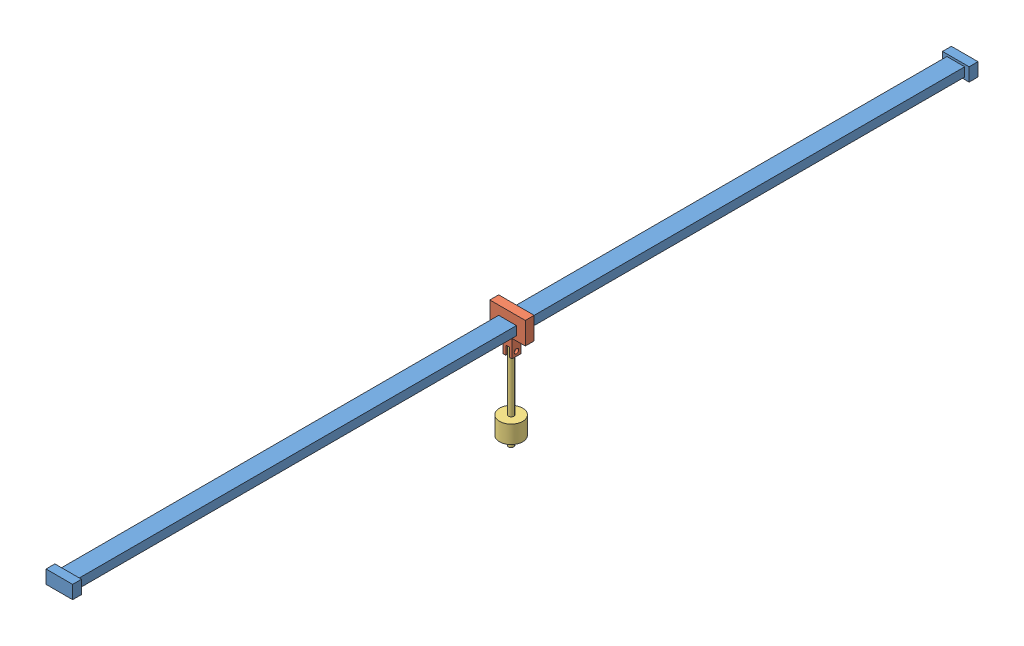
SolidWorks assembly PenduleTR, configuration Défaut. Lengths in mm.
Overall size (40 135 1020).
3 component instances, 3 part files, 7 mates.
Components (placement in the parent):
- bati-1: bati [Défaut] at (490.6862 31.3421 925.6549) size (30 15 1020)
- chariot-1: chariot [Défaut] at (490.6862 31.3421 925.6549) size (40 45 10)
- pendule-1: pendule [Défaut] at (489.6862 11.3421 925.6549) x (0 0 1) z (-1 0 0) size (26 100 26)
Mates (geometry in assembly coordinates):
- Coïncidente1: coincident anti-aligned: plane of bati-1 through (480.6862 26.3421 1425.6549) normal (0 -1 0); plane of chariot-1 through (480.6862 26.3421 920.6549) normal (0 1 0)
- Coïncidente2: coincident anti-aligned: plane of bati-1 through (480.6862 36.3421 1425.6549) normal (-1 0 0); plane of chariot-1 through (480.6862 36.3421 920.6549) normal (1 0 0)
- Coaxiale1: concentric anti-aligned: cylinder of chariot-1 through (470.6862 6.3421 925.6549) axis (1 0 0) radius 2.5; cylinder of pendule-1 through (502.6862 6.3421 925.6549) axis (-1 0 0) radius 2.5
- Tangent1: tangent anti-aligned: plane of chariot-1 through (492.6862 11.3421 920.6549) normal (-1 0 0); cylinder of pendule-1 through (489.6862 11.3421 925.6549) axis (0 1 0) radius 3
- PenduleCentre: distance = 495 mm anti-aligned: plane of chariot-1 through (490.6862 31.3421 930.6549) normal (0 0 1); plane of bati-1 through (490.6862 31.3421 1425.6549) normal (0 0 -1)
- Parallèle2: parallel aligned: line of chariot-1 through (510.6862 21.3421 920.6549) axis (0 1 0); cylinder of pendule-1 through (489.6862 11.3421 925.6549) axis (0 1 0) radius 3
- Distance2: distance = 480 mm anti-aligned: plane of bati-1 through (490.6862 31.3421 1425.6549) normal (0 0 -1); plane of chariot-1 through (490.6862 31.3421 945.6549) normal (0 0 1)
